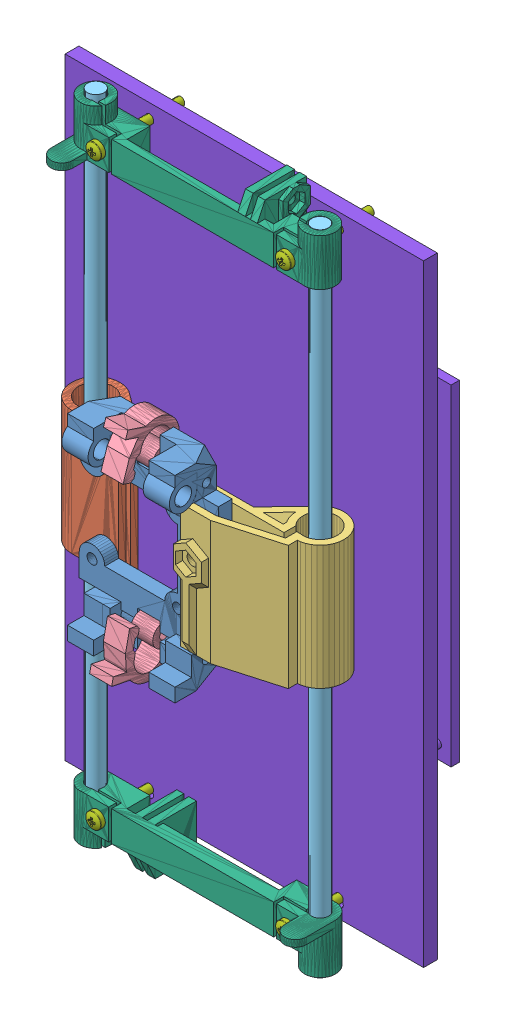
SolidWorks assembly carro y, configuration Valor predeterminado. Lengths in mm.
Overall size (130 236.83 57.93).
14 component instances, 8 part files, 23 mates.
Components (placement in the parent):
- carro y block-1: carro y block [Valor predeterminado] at origin size (50.44 77.5 17.04)
- y-bearing-holder-1: y-bearing-holder [Valor predeterminado] at (9.23 58.2501 0) x (-1 0 0) z (0 -1 0) size (25.76 17.52 45)
- y-bearing-idler solid-1: y-bearing-idler solid [Valor predeterminado] at (31.03 13.2501 12.0203) x (1 0 0) z (0 1 0.000001) size (51.23 29.53 45)
- lock-clip-1: lock-clip [Valor predeterminado] at (29.2201 -1.097 22.9284) x (0.000011 0.979089 -0.203434) z (-1 0.000028 0.000082) size (18.28 21.15 8)
- lock-clip-2: lock-clip [Valor predeterminado] at (21.2209 81.0258 15.845) x (-0.000002 -0.950715 0.310065) z (1 -0.000028 -0.000082) size (18.28 21.15 8)
- Barra lisa-1: Barra lisa [235 de 6mm] at (73.55 -81.7199 -8.7998) x (0 0.000001 -1) z (0 1 0.000001) size (6 6 235)
- Barra lisa-2: Barra lisa [235 de 6mm] at (-7.77 -79.8859 -8.76) x (0 0 -1) z (0 1 0) size (6 6 235)
- y-end-T2-5-1: y-end-T2-5 [Valor predeterminado] at (79.1694 -62.875 5.7414) x (-0.999999 0 0.001604) z (0 -1 -0.000001) size (92.54 26.86 16.94)
- y-end-T2-5-2: y-end-T2-5 [Valor predeterminado] at (-13.374 136.3785 5.7871) x (1 0 0.000545) z (0 1 0) size (92.54 26.86 16.94)
- Pan Head Cross Recess Screw_ISO-1: Pan Head Cross Recess Screw_ISO [ISO 7045 - M3 x 30 - Z --- 30N] at (-1.4904 141.8785 -0.8464) x (0.000545 0 -1) z (1 0.000001 0.000545) size (32.35 5.6 5.6)
- Pan Head Cross Recess Screw_ISO-2: Pan Head Cross Recess Screw_ISO [ISO 7045 - M3 x 30 - Z --- 30N] at (67.2788 -68.375 -0.8795) x (-0.001604 0.000001 -0.999999) z (0.999999 0.000001 -0.001604) size (32.35 5.6 5.6)
- Pan Head Cross Recess Screw_ISO-3: Pan Head Cross Recess Screw_ISO [ISO 7045 - M3 x 30 - Z --- 30N] at (-1.5011 -68.375 -0.7692) x (-0.001604 0.000001 -0.999999) z (0.999999 0.000001 -0.001604) size (32.35 5.6 5.6)
- Pan Head Cross Recess Screw_ISO-4: Pan Head Cross Recess Screw_ISO [ISO 7045 - M3 x 30 - Z --- 30N] at (67.2896 141.8785 -0.8089) x (0.000545 0 -1) z (-0.970759 0.240054 -0.000529) size (32.35 5.6 5.6)
- mesa-1: mesa [Valor predeterminado] at (32.8797 35.9862 -22) x (0 1 0) z (-1 0 -0.000001) size (222 13 130)
Mates (geometry in assembly coordinates):
- Concêntrico8: concentric aligned: circle of lock-clip-2; circle of carro y block-1
- Concêntrico9: concentric anti-aligned: circle of y-bearing-idler solid-1; cylinder of Barra lisa-1 through (73.55 153.2801 -8.7996) axis (0 -1 -0.000001) radius 3
- Coincidente15: coincident anti-aligned: plane of y-end-T2-5-2 through (2.5209 136.3785 -3.2442) normal (-0.000545 0 1); plane of Pan Head Cross Recess Screw_ISO-1 through (-1.4891 143.3785 -3.2464) normal (0.000545 0 -1)
- Concêntrico17: concentric anti-aligned: circle of y-end-T2-5-2; cylinder of Pan Head Cross Recess Screw_ISO-1 through (-1.5043 141.8785 24.5536) axis (-0.000545 0 1) radius 1.5
- Coincidente16: coincident anti-aligned: plane of y-end-T2-5-2 through (71.2909 136.3785 -3.2067) normal (-0.000545 0 1); plane of Pan Head Cross Recess Screw_ISO-4 through (66.9308 140.4223 -3.2091) normal (0.000545 0 -1)
- Concêntrico18: concentric anti-aligned: circle of y-end-T2-5-2; cylinder of Pan Head Cross Recess Screw_ISO-4 through (67.2757 141.8785 24.5911) axis (-0.000545 0 1) radius 1.5
- Coincidente17: coincident anti-aligned: plane of y-end-T2-5-1 through (-2.9145 -67.8619 -3.1669) normal (0.001604 -0.000001 0.999999); plane of Pan Head Cross Recess Screw_ISO-3 through (-1.505 -66.8749 -3.1692) normal (-0.001604 0.000001 -0.999999)
- Concêntrico19: concentric anti-aligned: circle of y-end-T2-5-1; cylinder of Pan Head Cross Recess Screw_ISO-3 through (-1.4604 -68.375 24.6308) axis (0.001604 -0.000001 0.999999) radius 1.5
- Coincidente18: coincident anti-aligned: plane of y-end-T2-5-1 through (63.265 -62.8749 -3.2731) normal (0.001604 -0.000001 0.999999); plane of Pan Head Cross Recess Screw_ISO-2 through (67.2749 -66.8749 -3.2795) normal (-0.001604 0.000001 -0.999999)
- Concêntrico20: concentric anti-aligned: circle of y-end-T2-5-1; cylinder of Pan Head Cross Recess Screw_ISO-2 through (67.3195 -68.375 24.5204) axis (0.001604 -0.000001 0.999999) radius 1.5
- Coincidente20: coincident aligned: plane of carro y block-1 through (0 0 0) normal (1 0 0); plane of assembly through (0 0 0) normal (1 0 0)
- Coincidente22: coincident aligned: plane of carro y block-1 through (0 0 0) normal (0 0 1); plane of assembly through (0 0 0) normal (0 0 1)
- Concêntrico22: concentric anti-aligned: circle of carro y block-1; circle of lock-clip-1
- Coincidente27: coincident: plane of carro y block-1 through (29.2183 0.0007 0.0001) normal (-1 0.000018 0.000036); line of lock-clip-1 through (29.2184 7.1831 -0.3841) axis (-0.00001 -0.979089 0.203434)
- Concêntrico23: concentric aligned: circle of carro y block-1; circle of y-bearing-idler solid-1
- Concêntrico24: concentric aligned: circle of carro y block-1; circle of y-bearing-idler solid-1
- Coincidente33: coincident anti-aligned: plane of carro y block-1 through (0 0 0) normal (0 0 1); plane of y-bearing-holder-1
- Coincidente34: coincident: plane of carro y block-1 through (21.219 64.7993 2.8001) normal (1 0 0); line of lock-clip-2 through (21.219 62.2546 -0.2694) axis (0.000001 0.950715 -0.310065)
- Concêntrico26: concentric aligned: circle of y-bearing-holder-1; cylinder of Barra lisa-2 through (-7.77 155.1141 -8.76) axis (0 -1 0) radius 3
- Paralelo2: parallel aligned: plane of Barra lisa-1; plane of Barra lisa-2
- Concêntrico27: concentric anti-aligned: cylinder of Barra lisa-2 through (-7.77 155.1141 -8.76) axis (0 -1 0) radius 3; circle of y-end-T2-5-2
- Concêntrico28: concentric aligned: cylinder of Barra lisa-1 through (73.55 153.2801 -8.7996) axis (0 -1 -0.000001) radius 3; circle of y-end-T2-5-1
- Distância1: distance = 22 mm anti-aligned: plane of carro y block-1 through (21.219 71.5002 0) normal (0.000001 0 -1); plane of mesa-1 through (-32.1203 146.9862 -22) normal (-0.000001 0 1)
